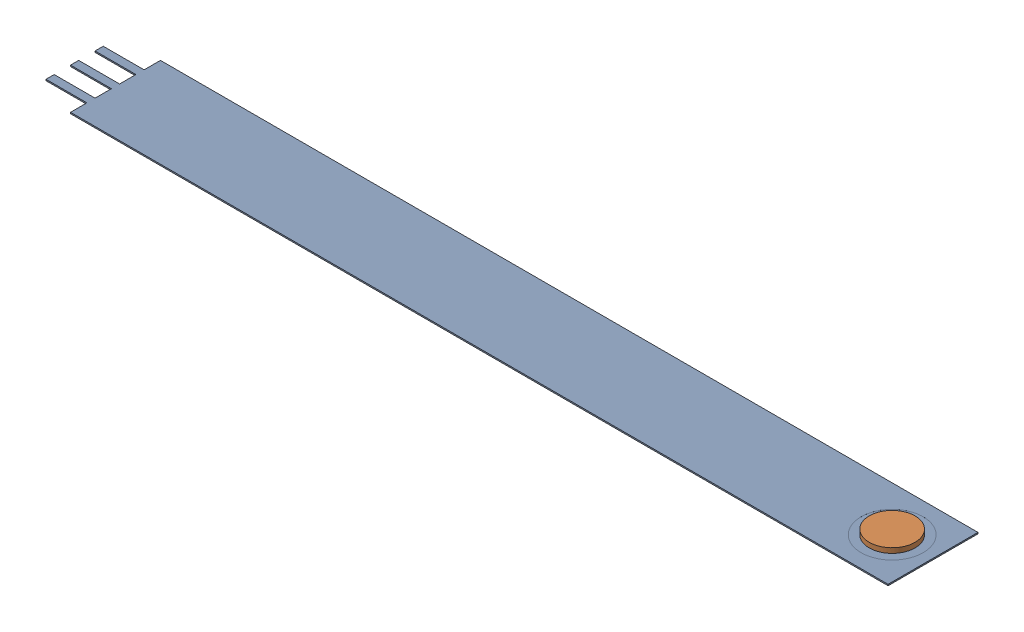
SolidWorks assembly A201_Puck, configuration Default. Lengths in mm.
Overall size (133.35 0.96 13.97).
2 component instances, 2 part files, 2 mates.
Components (placement in the parent):
- A201-1: A201 [Default] at (78.654 10.852 -6.6398) size (133.35 0.2 13.97)
- FLXLC-A-1: FLXLC-A [Default] at (78.654 11.0526 -6.6398) size (7.11 0.76 7.11)
Mates (geometry in assembly coordinates):
- Concentric1: concentric aligned: circle of A201-1; circle of FLXLC-A-1
- Coincident4: coincident anti-aligned: plane of A201-1 through (78.654 11.0526 -6.6398) normal (0 1 0); plane of FLXLC-A-1 through (78.654 11.0526 -6.6398) normal (0 -1 0)
